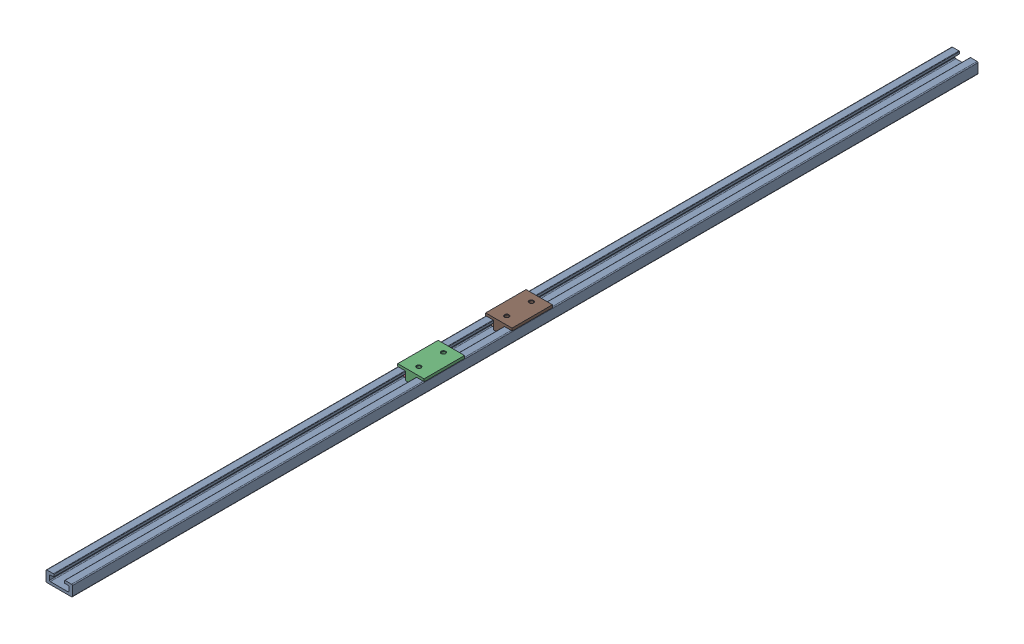
SolidWorks assembly 滑台滑轨装配, configuration 默认. Lengths in mm.
Overall size (30 15.25 1030).
11 component instances, 3 part files, 23 mates.
Components (placement in the parent):
- 滑轨1030d6di5.2dt40-1: 滑轨1030d6di5.2dt40 [默认] at (30.0997 6.25 -103.3848) size (30 12.5 1030)
- 滑台滚轴-1: 滑台滚轴 [默认] at (20.5997 5.875 -30.3848) x (1 0 0) z (0 0.854712 0.519103) size (2.5 6 6)
- 滑台46x30双孔d5di4.13dt28-1: 滑台46x30双孔d5di4.13dt28 [默认] at (30.0997 9 -11.3848) size (30 12.25 46)
- 滑台滚轴-2: 滑台滚轴 [默认] at (20.5997 5.875 7.6152) size (2.5 6 6)
- 滑台滚轴-3: 滑台滚轴 [默认] at (37.0997 5.875 -30.3848) x (1 0 0) z (0 0.854712 0.519103) size (2.5 6 6)
- 滑台滚轴-4: 滑台滚轴 [默认] at (37.0997 5.875 7.6152) x (1 0 0) z (0 0.854712 0.519103) size (2.5 6 6)
- 滑台滚轴-5: 滑台滚轴 [默认] at (20.5997 5.875 -130.3848) x (1 0 0) z (0 0.854712 0.519103) size (2.5 6 6)
- 滑台滚轴-6: 滑台滚轴 [默认] at (20.5997 5.875 -92.3848) size (2.5 6 6)
- 滑台滚轴-7: 滑台滚轴 [默认] at (37.0997 5.875 -92.3848) x (1 0 0) z (0 0.854712 0.519103) size (2.5 6 6)
- 滑台滚轴-8: 滑台滚轴 [默认] at (37.0997 5.875 -130.3848) x (1 0 0) z (0 0.854712 0.519103) size (2.5 6 6)
- 滑台46x30双孔d5di4.13dt28-2: 滑台46x30双孔d5di4.13dt28 [默认] at (30.0997 9 -111.3848) size (30 12.25 46)
Mates (geometry in assembly coordinates):
- 重合1: coincident anti-aligned: plane of 滑轨1030d6di5.2dt40-1 through (44.0997 0 411.6152) normal (0 -1 0)
- 同心2: concentric anti-aligned: cylinder of 滑台46x30双孔d5di4.13dt28-1 through (36.0997 5.875 7.6152) axis (1 0 0) radius 1.5; cylinder of 滑台滚轴-4 through (39.5997 5.875 7.6152) axis (-1 0 0) radius 1.5
- 重合2: coincident anti-aligned: plane of 滑台46x30双孔d5di4.13dt28-1 through (37.0997 7.375 7.6152) normal (1 0 0); plane of 滑台滚轴-4 through (37.0997 6.6952 6.2647) normal (-1 0 0)
- 同心8: concentric anti-aligned: cylinder of 滑台46x30双孔d5di4.13dt28-1 through (19.5997 5.875 7.6152) axis (1 0 0) radius 1.5; circle of 滑台滚轴-2
- 重合4: coincident anti-aligned: plane of 滑台46x30双孔d5di4.13dt28-1 through (23.0997 8.375 7.6152) normal (-1 0 0); plane of 滑台滚轴-2 through (23.0997 7.95 7.6152) normal (1 0 0)
- 同心3: concentric anti-aligned: cylinder of 滑台滚轴-1 through (23.0997 5.875 -30.3848) axis (-1 0 0) radius 1.5; cylinder of 滑台46x30双孔d5di4.13dt28-1 through (19.5997 5.875 -30.3848) axis (1 0 0) radius 1.5
- 重合5: coincident anti-aligned: plane of 滑台滚轴-1 through (23.0997 6.9521 -32.1583) normal (1 0 0); plane of 滑台46x30双孔d5di4.13dt28-1 through (23.0997 8.375 -30.3848) normal (-1 0 0)
- 同心4: concentric anti-aligned: cylinder of 滑台46x30双孔d5di4.13dt28-1 through (36.0997 5.875 -30.3848) axis (1 0 0) radius 1.5; cylinder of 滑台滚轴-3 through (39.5997 5.875 -30.3848) axis (-1 0 0) radius 1.5
- 重合6: coincident anti-aligned: plane of 滑台46x30双孔d5di4.13dt28-1 through (37.0997 7.375 -30.3848) normal (1 0 0); plane of 滑台滚轴-3 through (37.0997 6.6952 -31.7353) normal (-1 0 0)
- 重合7: coincident anti-aligned: plane of 滑轨1030d6di5.2dt40-1 through (20.0997 3 411.6152) normal (0 1 0); plane of 滑台46x30双孔d5di4.13dt28-1 through (30.0997 3 -11.3848) normal (0 -1 0)
- 重合8: coincident aligned: plane of 滑轨1030d6di5.2dt40-1 through (45.0997 11.5 411.6152) normal (1 0 0); plane of 滑台46x30双孔d5di4.13dt28-1 through (45.0997 15.25 -34.3848) normal (1 0 0)
- 距离1: distance = 400 mm aligned: plane of 滑台46x30双孔d5di4.13dt28-1 through (45.0997 15.25 11.6152) normal (0 0 1); plane of 滑轨1030d6di5.2dt40-1 through (16.0997 1 411.6152) normal (0 0 1)
- 同心9: concentric anti-aligned: circle of 滑台滚轴-6; cylinder of 滑台46x30双孔d5di4.13dt28-2 through (19.5997 5.875 -84.9839) axis (1 0 0) radius 1.5
- 重合10: coincident anti-aligned: plane of 滑台滚轴-7 through (37.0997 6.6952 -86.3344) normal (-1 0 0); plane of 滑台46x30双孔d5di4.13dt28-2 through (37.0997 7.375 -84.9839) normal (1 0 0)
- 重合11: coincident anti-aligned: plane of 滑台滚轴-5 through (23.0997 6.9521 -124.7575) normal (1 0 0); plane of 滑台46x30双孔d5di4.13dt28-2 through (23.0997 8.375 -122.9839) normal (-1 0 0)
- 重合12: coincident anti-aligned: plane of 滑台滚轴-8 through (37.0997 6.6952 -124.3344) normal (-1 0 0); plane of 滑台46x30双孔d5di4.13dt28-2 through (37.0997 7.375 -122.9839) normal (1 0 0)
- 重合13: coincident anti-aligned: plane of 滑台滚轴-6 through (23.0997 7.95 -84.9839) normal (1 0 0); plane of 滑台46x30双孔d5di4.13dt28-2 through (23.0997 8.375 -84.9839) normal (-1 0 0)
- 同心5: concentric anti-aligned: cylinder of 滑台滚轴-7 through (39.5997 5.875 -84.9839) axis (-1 0 0) radius 1.5; cylinder of 滑台46x30双孔d5di4.13dt28-2 through (36.0997 5.875 -84.9839) axis (1 0 0) radius 1.5
- 同心6: concentric anti-aligned: cylinder of 滑台滚轴-8 through (39.5997 5.875 -122.9839) axis (-1 0 0) radius 1.5; cylinder of 滑台46x30双孔d5di4.13dt28-2 through (36.0997 5.875 -122.9839) axis (1 0 0) radius 1.5
- 同心7: concentric anti-aligned: cylinder of 滑台滚轴-5 through (23.0997 5.875 -122.9839) axis (-1 0 0) radius 1.5; cylinder of 滑台46x30双孔d5di4.13dt28-2 through (19.5997 5.875 -122.9839) axis (1 0 0) radius 1.5
- 重合14: coincident anti-aligned: plane of 滑轨1030d6di5.2dt40-1 through (20.0997 3 411.6152) normal (0 1 0); plane of 滑台46x30双孔d5di4.13dt28-2 through (30.0997 3 -103.9839) normal (0 -1 0)
- 重合15: coincident aligned: plane of 滑轨1030d6di5.2dt40-1 through (45.0997 11.5 411.6152) normal (1 0 0); plane of 滑台46x30双孔d5di4.13dt28-2 through (45.0997 15.25 -126.9839) normal (1 0 0)
- 距离2: distance = 100 mm aligned: plane of 滑台46x30双孔d5di4.13dt28-2 through (15.0997 15.25 -134.3848) normal (0 0 -1); plane of 滑台46x30双孔d5di4.13dt28-1 through (15.0997 15.25 -34.3848) normal (0 0 -1)
